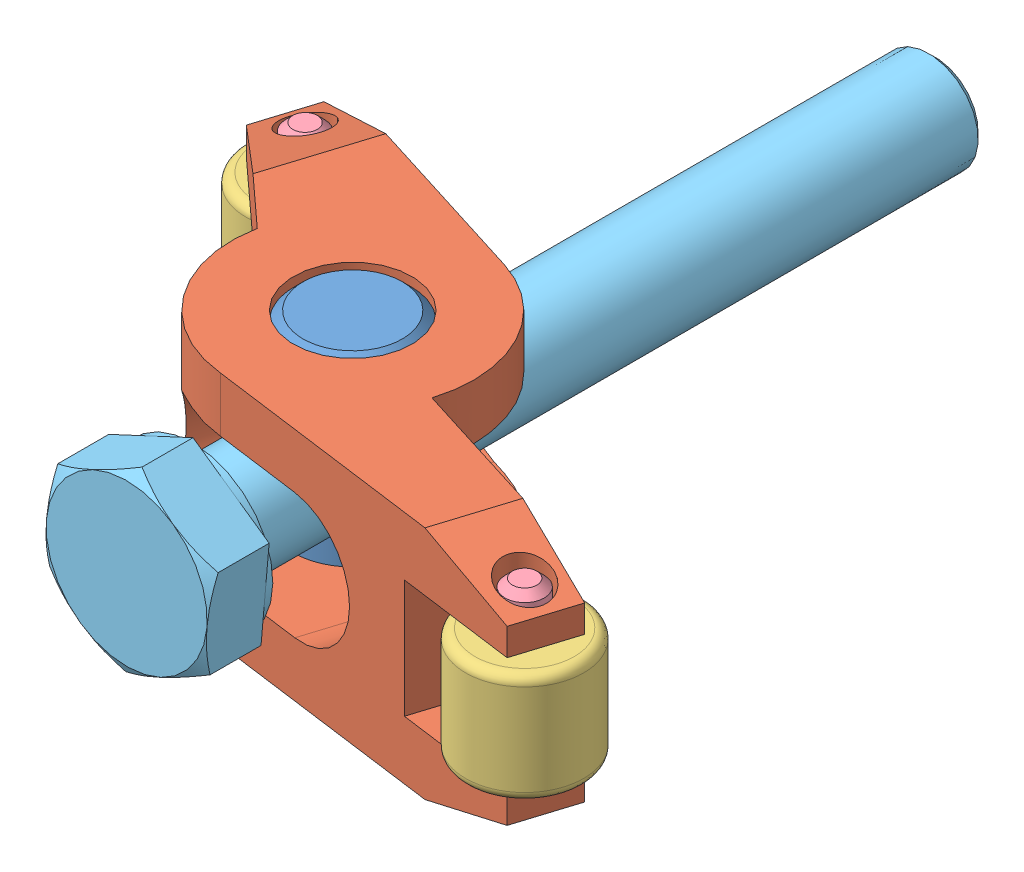
SolidWorks assembly Assem1.engine rocker arm assembly, configuration Default. Lengths in mm.
Overall size (54.33 19.05 65.3).
7 component instances, 5 part files, 12 mates.
Components (placement in the parent):
- Part 1.3-3: Part 1.3 [Default] at (6.6738 -15.2335 9.7195) size (9.53 19.05 9.53)
- Part 1.4(rocker arm)-2: Part 1.4(rocker arm) [Default] at (6.6738 -15.2085 9.7195) x (0.954223 0 0.299097) z (-0.299097 0 0.954223) size (50.82 19 19.53)
- Part1.2-3: Part1.2 [Default] at (-9.9538 -19.6585 -3.064) x (0.98448 0 0.175495) z (-0.175495 0 0.98448) size (9.53 8.9 9.53)
- Part1.2-4: Part1.2 [Default] at (30.7716 -19.6585 19.9347) x (0.987545 0 0.157338) z (-0.157338 0 0.987545) size (9.53 8.9 9.53)
- Part1.3-3: Part1.3 [Default] at (30.7716 -15.2085 19.9347) x (0 -1 0) z (0.977195 0 0.212345) size (15.87 3.17 3.17)
- Part1.3-4: Part1.3 [Default] at (-9.9538 -15.2085 -3.064) x (0 1 0) z (0.901042 0 0.433731) size (15.87 3.17 3.17)
- hex screw gradeab fine_iso-4: hex screw gradeab fine_iso [ISO 8676 - M8x1.0 x 60-N] at (6.4238 -15.2335 27.7195) x (0 0 -1) z (-0.422378 0.90642 0) size (65.3 15.01 13)
Mates (geometry in assembly coordinates):
- Concentric5: concentric: cylinder of Part 1.3-3 through (6.6738 -5.7085 9.7195) axis (0 -1 0) radius 4.765; cylinder of Part 1.4(rocker arm)-2 through (6.6738 -5.7085 9.7195) axis (0 -1 0) radius 4.765
- Coincident3: coincident: plane of Part 1.3-3 through (6.6738 -5.7085 9.7195) normal (0 1 0); plane of Part 1.4(rocker arm)-2 through (6.6738 -5.7085 9.7195) normal (0 1 0)
- Concentric6: concentric: cylinder of Part 1.4(rocker arm)-2 through (-13.0334 -29.7085 2.5416) axis (0 1 0) radius 1.905; cylinder of Part1.2-3 through (-13.0334 -10.7585 2.5416) axis (0 -1 0) radius 1.59
- Width3: width: plane of Part1.2-3 through (-13.0334 -10.7585 2.5416) normal (0 1 0); plane of Part1.2-3 through (-13.0334 -19.6585 2.5416) normal (0 -1 0); plane of Part 1.4(rocker arm)-2 through (-6.0608 -10.4435 -4.7501) normal (0 -1 0); plane of Part 1.4(rocker arm)-2 through (-6.0608 -19.9735 -4.7501) normal (0 1 0)
- Concentric7: concentric: cylinder of Part 1.4(rocker arm)-2 through (32.7298 -29.7085 12.1971) axis (0 1 0) radius 1.905; cylinder of Part1.2-4 through (32.7298 -10.7585 12.1971) axis (0 -1 0) radius 1.59
- Width4: width: plane of Part1.2-4 through (32.7298 -19.6585 12.1971) normal (0 -1 0); plane of Part1.2-4 through (32.7298 -10.7585 12.1971) normal (0 1 0); plane of Part 1.4(rocker arm)-2 through (25.6991 -10.4435 -4.8261) normal (0 -1 0); plane of Part 1.4(rocker arm)-2 through (25.6991 -19.9735 -4.8261) normal (0 1 0)
- Concentric8: concentric: cylinder of Part1.2-4 through (32.7298 -10.7585 12.1971) axis (0 -1 0) radius 1.59; cylinder of Part1.3-3 through (32.7298 -23.1435 12.1971) axis (0 1 0) radius 1.585
- Width5: width: plane of Part1.3-3 through (32.7298 -23.1435 12.1971) normal (0 -1 0); plane of Part1.3-3 through (32.7298 -7.2735 12.1971) normal (0 1 0); plane of Part 1.4(rocker arm)-2 through (25.6991 -19.9735 -4.8261) normal (0 1 0); plane of Part 1.4(rocker arm)-2 through (25.6991 -10.4435 -4.8261) normal (0 -1 0)
- Concentric9: concentric: circle of Part1.2-3; cylinder of Part1.3-4 through (-13.0334 -7.2735 2.5416) axis (0 -1 0) radius 1.585
- Width6: width: plane of Part1.3-4 through (-13.0334 -23.1435 2.5416) normal (0 -1 0); plane of Part1.3-4 through (-13.0334 -7.2735 2.5416) normal (0 1 0); plane of Part 1.4(rocker arm)-2 through (-6.0608 -19.9735 -4.7501) normal (0 1 0); plane of Part 1.4(rocker arm)-2 through (-6.0608 -10.4435 -4.7501) normal (0 -1 0)
- Concentric13: concentric: cylinder of Part 1.3-3 through (6.4238 -15.2335 0.1945) axis (0 0 1) radius 3.43; cylinder of hex screw gradeab fine_iso-4 through (6.4238 -15.2335 27.7195) axis (0 0 1) radius 4
- Distance1: distance = 12.7 mm: cylinder of Part 1.3-3 through (6.6738 -5.7085 9.7195) axis (0 -1 0) radius 4.765; plane of hex screw gradeab fine_iso-4 through (-0.3793 -18.4037 22.4195) normal (0 0 -1)
